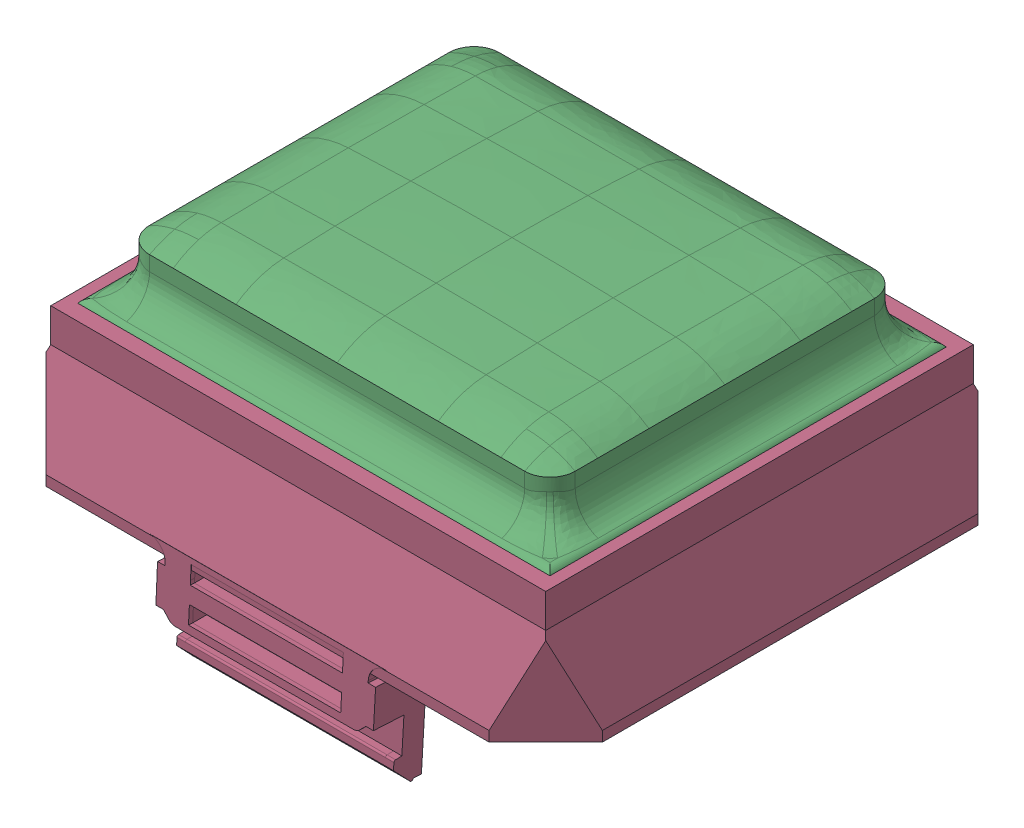
SolidWorks assembly Conti, configuration 默认. Lengths in mm.
Overall size (33 18.27 29.5).
5 component instances, 5 part files, 13 mates.
Components (placement in the parent):
- Contilensall-1: Contilensall [默认] at origin size (28.33 2.18 23.83)
- InsideSkin_conti-1: InsideSkin_conti [默认] at (0.0001 0 0.2499) size (23.8 5.48 19.29)
- ContiTopskin-1: ContiTopskin [默认] at (0.0001 2 0.2499) size (28.02 6.25 23.52)
- NewContiSupportBase-2: NewContiSupportBase [默认] at origin size (33 14.02 29.5)
- continuous-1: continuous [默认] at (-10.2499 23.3 7.7499) x (1 0 0) z (0 1 0) size (22 16 0.4)
Mates (geometry in assembly coordinates):
- 同心2: concentric anti-aligned: cylinder of InsideSkin_conti-1 through (10.8751 17.7531 8.6249) axis (0 1 0) radius 0.7; cylinder of Board3Con1612611OriginalSkin_TOP-1 through (10.8751 24 8.6249) axis (0 -1 0) radius 0.7
- 同心3: concentric anti-aligned: cylinder of InsideSkin_conti-1 through (10.8751 17.7531 -9.1251) axis (0 1 0) radius 0.7; cylinder of Board3Con1612611OriginalSkin_TOP-1 through (10.8751 24 -9.1251) axis (0 -1 0) radius 0.7
- 重合4: coincident aligned: plane of InsideSkin_conti-1 through (10.8751 19 -9.1251) normal (0 -1 0); plane of Board3Con1612611OriginalSkin_TOP-1 through (0.0001 19 0.2499) normal (0 -1 0)
- 重合6: coordinate: point of NewContiSupportBase-2
- 重合7: coincident anti-aligned: plane of Contilensall-1 through (13.75 19 -11.5) normal (0.939693 0.34202 0); plane of NewContiSupportBase-2 through (13.75 19 12.7803) normal (-0.939693 -0.34202 0)
- 同心5: concentric aligned: cylinder of Contilensall-1 through (13.3294 18.6938 -11.0794) axis (-0.323616 0.889126 0.323616) radius 0.5; cylinder of NewContiSupportBase-2 through (10.7866 25.6801 -8.5366) axis (-0.323616 0.889126 0.323616) radius 0.5
- 重合8: coincident anti-aligned: plane of Contilensall-1 through (0 18 0) normal (0 -1 0); plane of NewContiSupportBase-2 through (0 18 0) normal (0 1 0)
- 重合9: coincident anti-aligned: plane of lensall-1 through (0 19 0) normal (0 1 0); plane of Board3Con1612611OriginalSkin_TOP-1 through (0.0001 19 0.2499) normal (0 -1 0)
- 重合10: coincident anti-aligned: plane of ContiTopskin-1 through (0.0001 19 11.7499) normal (0 0 1); plane of NewContiSupportBase-2 through (-13.5999 21 11.7499) normal (0 0 -1)
- 重合11: coincident anti-aligned: plane of ContiTopskin-1 through (14.0001 19 0.2499) normal (1 0 0); plane of NewContiSupportBase-2 through (14.0001 21 11.7499) normal (-1 0 0)
- 宽度1: width aligned: plane of InsideSkin_conti-1 through (-11.3749 17.7531 -9.8251) normal (0 0 -1); plane of continuous-1 through (-11.3749 17.7531 9.3249) normal (0 0 1); plane of InsideSkin_conti-1 through (-11.2499 23.3 -8.2501) normal (0 0 -1); plane of continuous-1 through (-10.2499 23.7 7.7499) normal (0 0 1)
- 宽度2: width aligned: plane of continuous-1 through (-11.2499 23.3 -3.2352) normal (-1 0 0); plane of InsideSkin_conti-1 through (10.7501 23.7 7.7499) normal (1 0 0); plane of continuous-1 through (-12.0749 17.7531 -9.1251) normal (-1 0 0); plane of InsideSkin_conti-1 through (11.5751 17.7531 -9.1251) normal (1 0 0)
- 重合12: coincident aligned: line of InsideSkin_conti-1 through (-10.2499 23.7 -5.2501) axis (0 0 -1); line of continuous-1 through (-10.2499 23.7 -5.2501) axis (0 0 -1)
